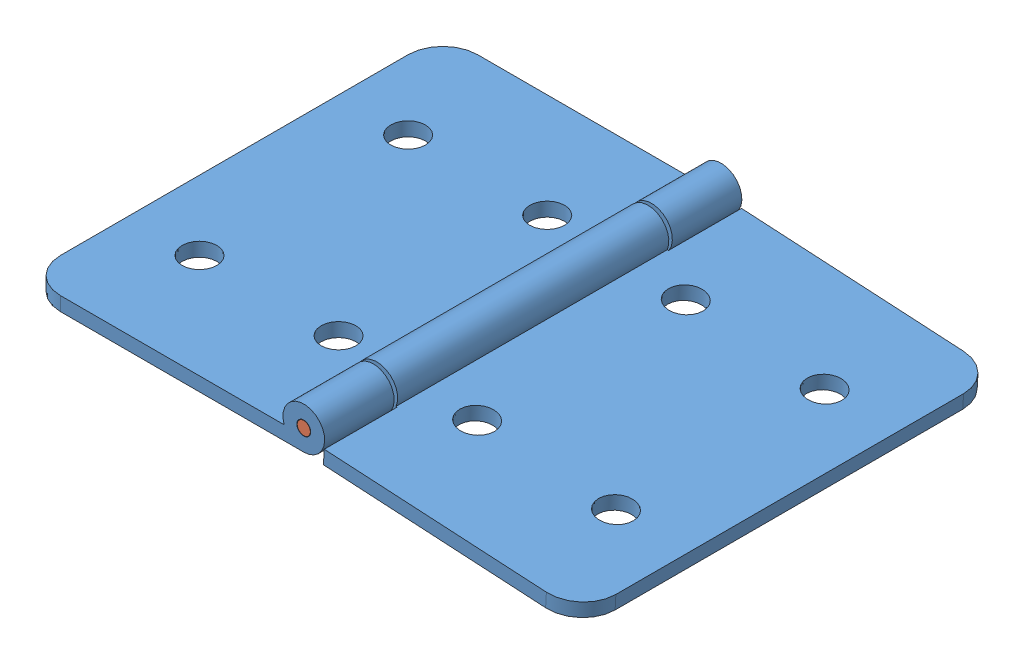
SolidWorks assembly hinge, configuration Default. Lengths in mm.
Overall size (80.11 8.44 60).
3 component instances, 2 part files, 3 mates.
Components (placement in the parent):
- hinge-side-1: hinge-side [A] at origin size (43 6 60)
- hinge-side-2: hinge-side [B] at (-0.171 0.0049 0) x (-0.998374 0.057006 0) z (0 0 -1) size (43 6 60)
- hinge-pin-1: hinge-pin [Default] at (0 3 -30) x (1 0 0) z (0 -1 0) size (1.9 60 1.9)
Mates (geometry in assembly coordinates):
- Hinge1: hinge = 0.057037 rad aligned: cylinder of hinge-side-1 through (0 3 -38.4853) axis (0 0 1) radius 1; cylinder of hinge-side-2 through (0 3 38.4853) axis (0 0 -1) radius 1; plane of hinge-side-1 through (-40 2 30) normal (0 0 1); plane of hinge-side-2 through (39.8779 -0.2786 30) normal (0 0 1); plane of hinge-side-1 through (0 2 0) normal (0 1 0); plane of hinge-side-2 through (-0.057 2.0016 0) normal (0.057006 0.998374 0)
- Concentric2: concentric anti-aligned: cylinder of hinge-side-1 through (0 3 -38.4853) axis (0 0 1) radius 1; cylinder of hinge-pin-1 through (0 3 30) axis (0 0 -1) radius 0.95
- Coincident1: coincident aligned: plane of hinge-side-1 through (-40 2 30) normal (0 0 1); plane of hinge-pin-1 through (0 3 30) normal (0 0 1)
